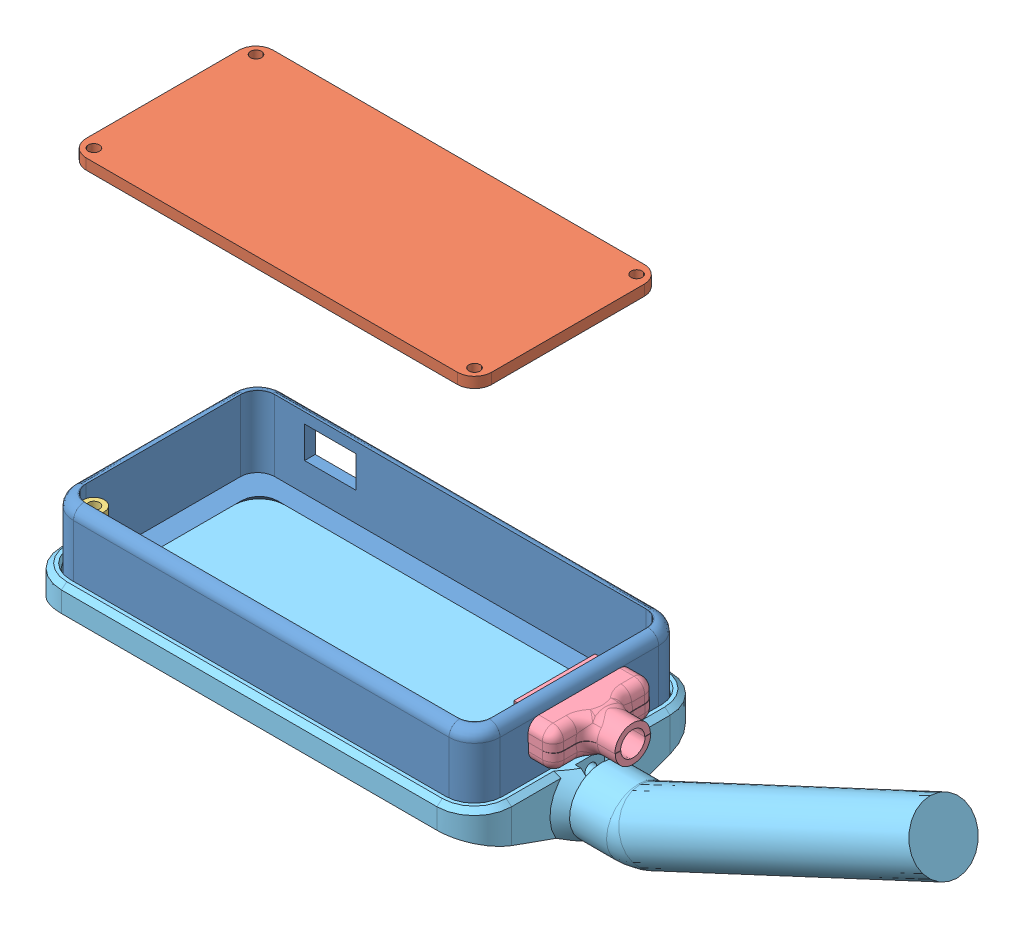
SolidWorks assembly control, configuration Predeterminado. Lengths in mm.
Overall size (236.28 174.5 65.6).
6 component instances, 5 part files, 14 mates.
Components (placement in the parent):
- carcasaControlInnova-1: carcasaControlInnova [Predeterminado] at (-11.8602 -22.7964 120) size (120 22 59)
- tapaa-1: tapaa [Predeterminado] at (-13.0613 80.3217 111.3032) x (0 0 -1) z (0 1 0) size (52.54 114 3)
- poste2-1: poste2 [Predeterminado] at (-65.4073 -14.5964 143.0302) x (1 0 0) z (0 -1 0) size (10 10 14)
- sujetaCable-1: sujetaCable [Predeterminado] at (48.1541 -8.9464 120.05) x (0 0 -1) z (0 1 0) size (28.8 22 5.48)
- sujetaCable-2: sujetaCable [Predeterminado] at (48.167 -9.0464 119.95) x (0 0 1) z (0 -1 0) size (28.8 22 5.48)
- soporte2-1: soporte2 [Predeterminado] at (150.5962 12.0262 120.0445) x (-0.906308 -0.422618 0) z (0 0 -1) size (224.91 76.76 65.6)
Mates (geometry in assembly coordinates):
- Distancia1: distance = 3 mm anti-aligned: plane of carcasaControlInnova-1 through (-64.6602 -20.7964 142.3) normal (0 1 0); plane of poste2-1 through (-65.4073 -17.7964 143.0302) normal (0 -1 0)
- Coincidente2: coincident anti-aligned: plane of carcasaControlInnova-1 through (-64.0855 -0.7964 146.5) normal (0 0 -1); plane of poste2-1 through (-65.4073 -17.7964 146.5) normal (0 0 1)
- Coincidente3: coincident anti-aligned: plane of carcasaControlInnova-1 through (-68.8602 -0.7964 98.2746) normal (1 0 0); plane of poste2-1 through (-68.8602 -17.7964 143.0302) normal (-1 0 0)
- Coincidente4: coincident anti-aligned: plane of carcasaControlInnova-1 through (-68.8602 -0.7964 98.2746) normal (1 0 0); plane of tapaa-1 through (-68.8602 83.3217 141.7238) normal (-1 0 0)
- Coincidente5: coincident anti-aligned: plane of carcasaControlInnova-1 through (-68.8602 -0.7964 98.2746) normal (1 0 0); plane of tapaa-1 through (-68.8602 83.3217 141.7238) normal (-1 0 0)
- Coincidente6: coincident anti-aligned: plane of carcasaControlInnova-1 through (-64.0855 -0.7964 146.5) normal (0 0 -1); plane of tapaa-1 through (40.3637 83.3217 146.5) normal (0 0 1)
- Coincidente7: coincident anti-aligned: plane of carcasaControlInnova-1 through (38.1398 -3.7964 131.45) normal (0 -1 0); plane of sujetaCable-1 through (41.1541 -3.7964 131.45) normal (0 1 0)
- Coincidente8: coincident anti-aligned: plane of carcasaControlInnova-1 through (38.1398 -3.7964 131.45) normal (0 0 -1); plane of sujetaCable-1 through (41.1541 -14.0964 131.45) normal (0 0 1)
- Coincidente9: coincident anti-aligned: plane of carcasaControlInnova-1 through (38.1398 -14.1964 131.45) normal (0 1 0); plane of sujetaCable-2 through (41.167 -14.1964 108.55) normal (0 -1 0)
- Coincidente10: coincident anti-aligned: plane of carcasaControlInnova-1 through (38.1398 -3.7964 108.55) normal (0 0 1); plane of sujetaCable-2 through (41.167 -3.8964 108.55) normal (0 0 -1)
- Coincidente11: coincident anti-aligned: plane of carcasaControlInnova-1 through (-64.6602 -22.7964 142.3) normal (0 -1 0); plane of soporte-1 through (48.1381 -22.7964 90.5) normal (0 1 0)
- Coincidente12: coincident aligned: plane of carcasaControlInnova-1 through (-64.6602 -0.7964 90.5) normal (0 0 -1); plane of soporte-1 through (48.1381 -25.7964 90.5) normal (0 0 -1)
- Coincidente13: coincident anti-aligned: plane of carcasaControlInnova-1 through (-64.6602 -22.7964 142.3) normal (0 -1 0); plane of soporte2-1 through (150.5962 -22.7964 120.0445) normal (0 1 0)
- Paralelo1: parallel aligned: plane of carcasaControlInnova-1 through (-64.6602 -0.7964 90.5) normal (0 0 -1); plane of soporte2-1 through (51.4023 -17.7964 87.2445) normal (0 0 -1)
